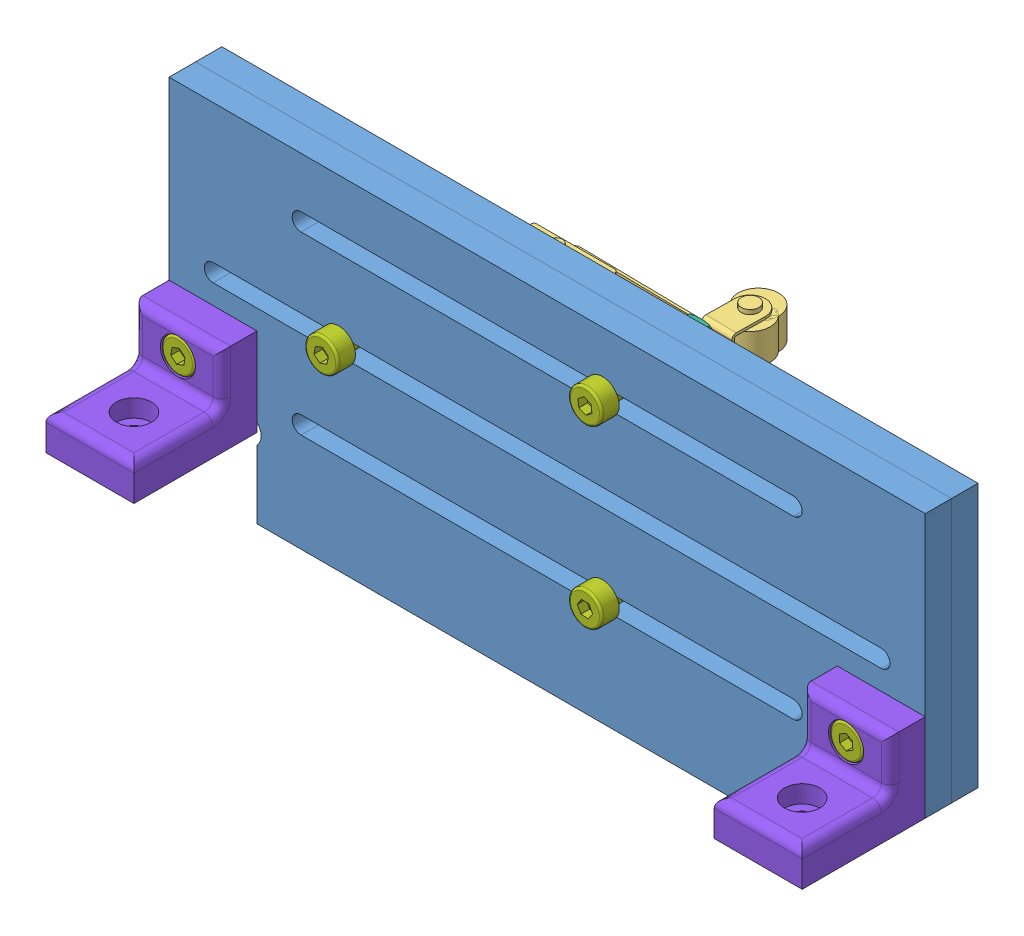
SolidWorks assembly cfc_ouvert, configuration Défaut. Lengths in mm.
Overall size (86 39 42.4).
21 component instances, 8 part files, 44 mates.
Components (placement in the parent):
- cfc-platine-1: cfc-platine [Défaut] at (140.8628 -70 0) x (0 0 1) z (0 -1 0) size (3 86 39)
- Grove microswitch v1.0-1: Grove microswitch v1.0 [Défaut] at (-48.6908 22.25 -3.344) x (-1 0 0) z (0 -1 0) size (41.8 22.4 23.6)
  - PCB grove 20x40-1: PCB grove 20x40 [Défaut] at (-1.988 -1.344 0) size (41.8 1.6 23.6)
  - microswitch 10T85-1: microswitch 10T85 [Défaut] at (9.562 0.256 0) size (22.48 22.4 6.4)
  - Connecteur Grove (coudé CMS)-1: Connecteur Grove (coudé CMS) [Défaut] at (-21.488 0.256 0) x (0 0 -1) z (0 1 0) size (12 10 5)
- entretoise-grove-1: entretoise-grove [Défaut] at (-66.7028 22.25 -2) x (1 0.000242 0) z (0 0 1) size (4 4 2)
- entretoise-grove-2: entretoise-grove [Défaut] at (-36.7028 32.25 -2) size (4 4 2)
- entretoise-grove-3: entretoise-grove [Défaut] at (-36.7028 12.25 -2) size (4 4 2)
- ecrou-h-2: ecrou-h [6007 HU M2] at (-36.7028 32.25 -5.2) x (-0.866025 0.5 0) z (-0.5 -0.866025 0) size (4 1.6 4.62)
- ecrou-h-3: ecrou-h [6007 HU M2] at (-36.7028 12.25 -5.2) x (0.866025 0.5 0) z (-0.5 0.866025 0) size (4 1.6 4.62)
- vis-chc-1: vis-chc [Vis CHC M2x12] at (-36.7028 32.25 6) x (0.144676 -0.989479 0) z (-0.989479 -0.144676 0) size (3.8 14 3.8)
- vis-chc-2: vis-chc [Vis CHC M2x12] at (-36.7028 12.25 6) x (0.999846 -0.017534 0) z (-0.017534 -0.999846 0) size (3.8 14 3.8)
- vis-chc-3: vis-chc [Vis CHC M2x12] at (-66.7028 22.25 6) x (-0.77641 0.630228 0) z (0.630228 0.77641 0) size (3.8 14 3.8)
- vis-chc-5: vis-chc [Vis CHC M2x10] at (-5 16 8) x (0.048861 -0.998806 0) z (-0.998806 -0.048861 0) size (3.8 12 3.8)
- vis-chc-6: vis-chc [Vis CHC M2x10] at (-81 16 8) x (-0.923728 -0.383049 0) z (-0.383049 0.923728 0) size (3.8 12 3.8)
- ecrou-h-6: ecrou-h [6007 HU M2] at (-81 16 -1.6) x (1 0 0) z (0 1 0) size (4 1.6 4.62)
- ecrou-h-8: ecrou-h [6007 HU M2] at (-5 16 -1.6) x (1 0 0) z (0 1 0) size (4 1.6 4.62)
- cfc-platine-2: cfc-platine [Défaut] at (140.8628 -70 3) x (0 0 1) z (0 -1 0) size (3 86 39)
- ecrou-h-4: ecrou-h [6007 HU M2] at (-66.7028 22.25 -5.2) x (1 0 0) z (0 1 0) size (4 1.6 4.62)
- equerre-basse-1: equerre-basse [Défaut] at (-81 9 6) size (10 10 14)
- equerre-basse-2: equerre-basse [Défaut] at (-5 9 6) size (10 10 14)
Mates (geometry in assembly coordinates):
- Coaxiale1: concentric anti-aligned: cylinder of Grove microswitch v1.0-1/PCB grove 20x40-1 through (-36.7028 12.25 -3.6) axis (0 0 1) radius 1.1; cylinder of entretoise-grove-3 through (-36.7028 12.25 0) axis (0 0 -1) radius 1.2
- Coïncidente4: coincident anti-aligned: plane of Grove microswitch v1.0-1/PCB grove 20x40-1 through (-46.7028 22.25 -2) normal (0 0 1); plane of entretoise-grove-3 through (-36.7028 12.25 -2) normal (0 0 -1)
- Coaxiale2: concentric anti-aligned: cylinder of Grove microswitch v1.0-1/PCB grove 20x40-1 through (-66.7028 22.25 -3.6) axis (0 0 1) radius 1.1; cylinder of entretoise-grove-1 through (-66.7028 22.25 0) axis (0 0 -1) radius 1.2
- Coïncidente5: coincident anti-aligned: plane of Grove microswitch v1.0-1/PCB grove 20x40-1 through (-46.7028 22.25 -2) normal (0 0 1); plane of entretoise-grove-1 through (-66.7028 22.25 -2) normal (0 0 -1)
- Coaxiale3: concentric anti-aligned: cylinder of Grove microswitch v1.0-1/PCB grove 20x40-1 through (-36.7028 32.25 -3.6) axis (0 0 1) radius 1.1; cylinder of entretoise-grove-2 through (-36.7028 32.25 0) axis (0 0 -1) radius 1.2
- Coïncidente6: coincident anti-aligned: plane of Grove microswitch v1.0-1/PCB grove 20x40-1 through (-46.7028 22.25 -2) normal (0 0 1); plane of entretoise-grove-2 through (-36.7028 32.25 -2) normal (0 0 -1)
- Coïncidente7: coincident anti-aligned: plane of cfc-platine-1 through (-8.8686 8.8686 0) normal (0 0 -1); plane of entretoise-grove-1 through (-66.7028 22.25 0) normal (0 0 1)
- Parallèle4: parallel aligned: plane of cfc-platine-1 through (-86 39 3) normal (-1 0 0); plane of Grove microswitch v1.0-1/PCB grove 20x40-1 through (-66.7028 22.25 -3.6) normal (-1 0 0)
- Parallèle3: parallel aligned: plane of cfc-platine-1 through (-10 0 3) normal (0 -1 0); plane of Grove microswitch v1.0-1/PCB grove 20x40-1 through (-46.7028 12.25 -3.6) normal (0 -1 0)
- Coaxiale4: concentric aligned: cylinder of Grove microswitch v1.0-1/PCB grove 20x40-1 through (-36.7028 32.25 -3.6) axis (0 0 1) radius 1.1; cylinder of vis-chc-1 through (-36.7028 32.25 -6) axis (0 0 1) radius 1
- Coaxiale5: concentric aligned: cylinder of Grove microswitch v1.0-1/PCB grove 20x40-1 through (-66.7028 22.25 -3.6) axis (0 0 1) radius 1.1; cylinder of vis-chc-3 through (-66.7028 22.25 -6) axis (0 0 1) radius 1
- Coaxiale6: concentric aligned: cylinder of Grove microswitch v1.0-1/PCB grove 20x40-1 through (-36.7028 12.25 -3.6) axis (0 0 1) radius 1.1; cylinder of vis-chc-2 through (-36.7028 12.25 -6) axis (0 0 1) radius 1
- Coaxiale7: concentric anti-aligned: cylinder of ecrou-h-2 through (-36.7028 32.25 -3.6) axis (0 0 -1) radius 0.7835; cylinder of vis-chc-1 through (-36.7028 32.25 -6) axis (0 0 1) radius 1
- Coaxiale8: concentric anti-aligned: cylinder of ecrou-h-3 through (-36.7028 12.25 -3.6) axis (0 0 -1) radius 0.7835; cylinder of vis-chc-2 through (-36.7028 12.25 -6) axis (0 0 1) radius 1
- Parallèle5: parallel aligned: plane of cfc-platine-1 through (0 39 3) normal (0 1 0); plane of ecrou-h-2 through (-37.8575 34.25 -3.6) normal (0 1 0)
- Parallèle7: parallel aligned: plane of ecrou-h-2 through (-37.8575 34.25 -3.6) normal (0 1 0); plane of ecrou-h-3 through (-37.8575 14.25 -3.6) normal (0 1 0)
- Tangent1: tangent anti-aligned: plane of cfc-platine-1 through (-15 31.25 3) normal (0 1 0); cylinder of vis-chc-1 through (-36.7028 32.25 -6) axis (0 0 1) radius 1
- Coïncidente17: coincident anti-aligned: plane of cfc-platine-1 through (-8.8686 8.8686 3) normal (0 0 1); plane of cfc-platine-2 through (-8.8686 8.8686 3) normal (0 0 -1)
- Coïncidente19: coincident aligned: plane of cfc-platine-1 through (-86 39 3) normal (-1 0 0); plane of cfc-platine-2 through (-86 39 6) normal (-1 0 0)
- Coïncidente20: coincident aligned: plane of cfc-platine-1 through (0 39 3) normal (0 1 0); plane of cfc-platine-2 through (0 39 6) normal (0 1 0)
- Coïncidente21: coincident anti-aligned: plane of vis-chc-3 through (-66.7028 22.25 6) normal (0 0 -1); plane of cfc-platine-2 through (-8.8686 8.8686 6) normal (0 0 1)
- Coaxiale9: concentric anti-aligned: cylinder of vis-chc-3 through (-66.7028 22.25 -6) axis (0 0 1) radius 1; cylinder of ecrou-h-4 through (-66.7028 22.25 -3.6) axis (0 0 -1) radius 0.7835
- Parallèle8: parallel aligned: plane of Grove microswitch v1.0-1/microswitch 10T85-1 through (-64.7028 19.25 -13.9) normal (-1 0 0); plane of ecrou-h-4 through (-68.7028 21.0953 -3.6) normal (-1 0 0)
- Coïncidente23: coincident anti-aligned: plane of Grove microswitch v1.0-1/PCB grove 20x40-1 through (-46.7028 22.25 -3.6) normal (0 0 -1); plane of ecrou-h-4 through (-64.7028 21.0953 -3.6) normal (0 0 1)
- Coïncidente24: coincident anti-aligned: plane of vis-chc-1 through (-36.7028 32.25 6) normal (0 0 -1); plane of cfc-platine-2 through (-8.8686 8.8686 6) normal (0 0 1)
- Coïncidente25: coincident anti-aligned: plane of Grove microswitch v1.0-1/PCB grove 20x40-1 through (-46.7028 22.25 -3.6) normal (0 0 -1); plane of ecrou-h-2 through (-37.8575 34.25 -3.6) normal (0 0 1)
- Parallèle9: parallel aligned: plane of Grove microswitch v1.0-1/PCB grove 20x40-1 through (-46.7028 32.25 -3.6) normal (0 1 0); plane of ecrou-h-2 through (-37.8575 34.25 -3.6) normal (0 1 0)
- Coïncidente28: coincident anti-aligned: plane of Grove microswitch v1.0-1/PCB grove 20x40-1 through (-46.7028 22.25 -3.6) normal (0 0 -1); plane of ecrou-h-3 through (-34.3934 12.25 -3.6) normal (0 0 1)
- Coïncidente29: coincident anti-aligned: plane of cfc-platine-2 through (-8.8686 8.8686 6) normal (0 0 1); plane of equerre-1 through (-81 9 6) normal (0 0 -1)
- Coïncidente30: coincident aligned: plane of cfc-platine-2 through (-86 39 6) normal (-1 0 0); plane of equerre-1 through (-86 19 10) normal (-1 0 0)
- Coïncidente31: coincident aligned: plane of cfc-platine-2 through (-78.726 9 6) normal (0 -1 0); plane of equerre-1 through (-86 9 10) normal (0 -1 0)
- Coaxiale10: concentric aligned: cylinder of equerre-1 through (-81 16 6) axis (0 0 1) radius 1.1; cylinder of vis-chc-6 through (-81 16 -2) axis (0 0 1) radius 1
- Coaxiale13: concentric anti-aligned: cylinder of cfc-platine-2 through (-5 16 6) axis (0 0 -1) radius 1; cylinder of vis-chc-5 through (-5 16 -2) axis (0 0 1) radius 1
- Coïncidente35: coincident anti-aligned: plane of equerre-1 through (-81 16 8) normal (0 0 1); plane of vis-chc-6 through (-81 16 8) normal (0 0 -1)
- Coïncidente36: coincident aligned: plane of equerre-1 through (-86 9 10) normal (0 -1 0); plane of equerre-2 through (-10 9 10) normal (0 -1 0)
- Coaxiale14: concentric anti-aligned: cylinder of cfc-platine-2 through (-5 16 6) axis (0 0 -1) radius 1; cylinder of equerre-2 through (-5 16 6) axis (0 0 1) radius 1.1
- Coaxiale17: concentric anti-aligned: cylinder of vis-chc-6 through (-81 16 -2) axis (0 0 1) radius 1; cylinder of ecrou-h-6 through (-81 16 0) axis (0 0 -1) radius 0.7835
- Coaxiale19: concentric anti-aligned: cylinder of vis-chc-5 through (-5 16 -2) axis (0 0 1) radius 1; cylinder of ecrou-h-8 through (-5 16 0) axis (0 0 -1) radius 0.7835
- Coïncidente38: coincident anti-aligned: plane of cfc-platine-1 through (-8.8686 8.8686 0) normal (0 0 -1); plane of ecrou-h-8 through (-3 14.8453 0) normal (0 0 1)
- Parallèle10: parallel aligned: plane of cfc-platine-1 through (0 9 3) normal (1 0 0); plane of ecrou-h-8 through (-3 17.1547 0) normal (1 0 0)
- Coïncidente44: coincident anti-aligned: plane of cfc-platine-1 through (-8.8686 8.8686 0) normal (0 0 -1); plane of ecrou-h-6 through (-79 14.8453 0) normal (0 0 1)
- Parallèle13: parallel aligned: plane of cfc-platine-1 through (-86 39 3) normal (-1 0 0); plane of ecrou-h-6 through (-83 14.8453 0) normal (-1 0 0)
- Coïncidente45: coincident anti-aligned: plane of cfc-platine-2 through (-8.8686 8.8686 6) normal (0 0 1); plane of equerre-2 through (-5 9 6) normal (0 0 -1)
- Coïncidente46: coincident anti-aligned: plane of vis-chc-5 through (-5 16 8) normal (0 0 -1); plane of equerre-2 through (-5 16 8) normal (0 0 1)
